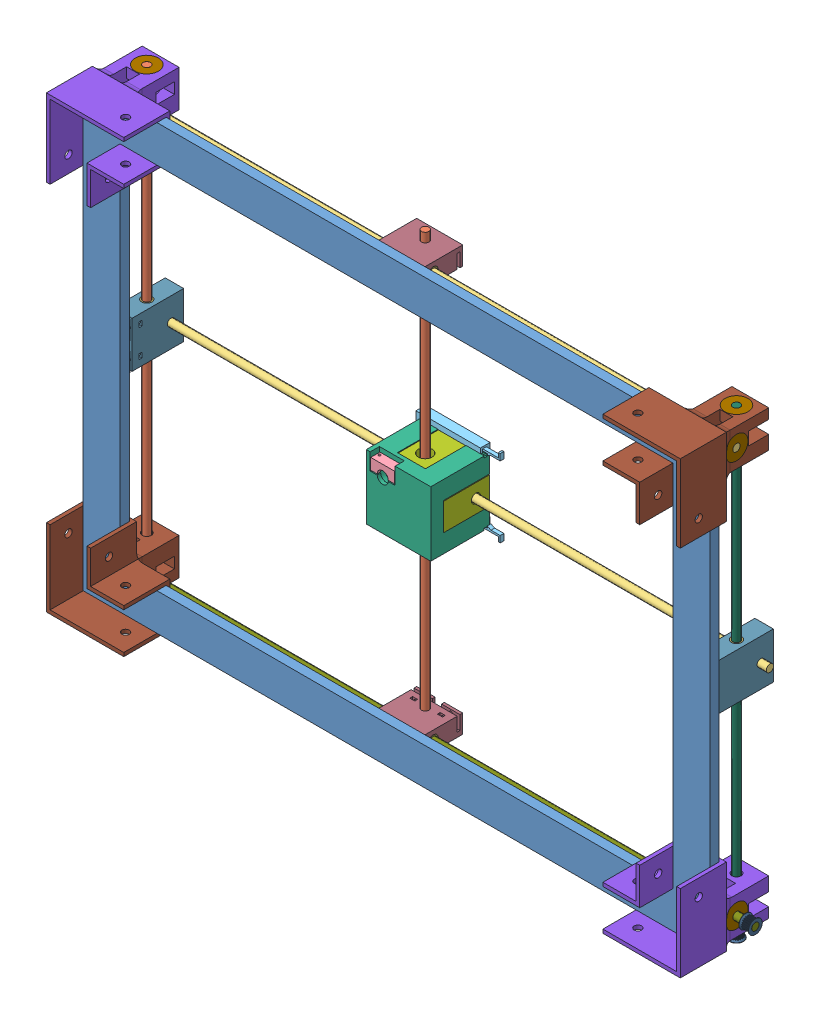
SolidWorks assembly Assemblage_XY, configuration Défaut. Lengths in mm.
Overall size (711.84 510.5 125.29).
50 component instances, 16 part files, 70 mates.
Components (placement in the parent):
- Cadre_XY-1: Cadre_XY [Défaut] at (379.0068 -247.2078 675) size (680 480 10)
- AXE_8X480-2: AXE_8X480 [Défaut] at (-280.9932 -247.2078 636) x (0.987721 0 0.156231) z (0 1 0) size (8 8 480)
- AXE_8X680-1: AXE_8X680 [Défaut] at (379.0068 212.7922 656) x (0 0.013067 0.999915) z (-1 0 0) size (8 8 680)
- AXE_8X480-3: AXE_8X480 [Défaut] at (24.9016 232.7922 639.7) x (0.999527 0 0.030742) z (0 -1 0) size (8 8 480)
- AXE_8X680-3: AXE_8X680 [Défaut] at (-300.9932 -12.6024 619.7) x (0 -0.696158 -0.717888) z (1 0 0) size (8 8 680)
- P3DMIPC-Tête_complete-1: P3DMIPC-Tête_complete [Défaut] at (-19.2911 0.7676 635.2981) x (0 1 0) z (1 0 0) size (84 69 89)
  - P3DMIPC-Clip_Buse_E3D-1: P3DMIPC-Clip_Buse_E3D [Défaut] at (17.0518 23.4109 40.0035) x (1 0 0) z (0 1 0) size (12 26 10)
  - P3DMIPC-Clip_tête-1: P3DMIPC-Clip_tête [Défaut] at (26.9018 -25.0891 4.5597) x (1 0 0) z (0 -1 0) size (84 89 10.5)
  - P3DMIPC-Porte_Buse_E3DX1-1: P3DMIPC-Porte_Buse_E3DX1 [Défaut] at (22.03 33.4019 79.1927) x (0 0 1) z (0 -1 0) size (70 70 64)
  - P3DMIPC-Chariot-1: P3DMIPC-Chariot [Défaut] at (-48.37 -30.5981 79.1927) size (70 50 70)
- Angle_magique_G-1: Angle_magique_G [Défaut] at (379.0068 -247.2078 675) x (-1 0 0) z (0 0 -1) size (91.34 90 104)
- F608ZZ-1: F608ZZ [Défaut] at (372.0068 -227.2078 656) x (0 -0.924225 -0.381849) z (1 0 0) size (25 25 7)
- Angle_magique_G-4: Angle_magique_G [Défaut] at (-300.9932 232.7922 675) x (1 0 0) z (0 0 -1) size (91.34 90 104)
- pulley_gt2_3mm_20t-10: pulley_gt2_3mm_20t [Défaut] at (-280.9932 209.5422 636) x (0.106795 0 0.994281) z (0 1 0) size (15 15 10.5)
- pulley_gt2_3mm_20t-11: pulley_gt2_3mm_20t [Défaut] at (-277.7432 212.7922 656) x (0 0.106795 0.994281) z (-1 0 0) size (15 15 10.5)
- pulley_gt2_3mm_20t-12: pulley_gt2_3mm_20t [Défaut] at (-280.9932 -236.4578 636) x (-0.771074 0 0.636745) z (0 1 0) size (15 15 10.5)
- pulley_gt2_3mm_20t-13: pulley_gt2_3mm_20t [Défaut] at (-277.7432 -227.2078 656) x (0 0.106795 0.994281) z (-1 0 0) size (15 15 10.5)
- pulley_gt2_3mm_20t-15: pulley_gt2_3mm_20t [Défaut] at (359.0068 222.0422 636) x (-0.106795 0 0.994281) z (0 -1 0) size (15 15 10.5)
- pulley_gt2_3mm_20t-16: pulley_gt2_3mm_20t [Défaut] at (368.2568 212.7922 656) x (0 0.106795 0.994281) z (-1 0 0) size (15 15 10.5)
- F608ZZ-2: F608ZZ [Défaut] at (-280.9932 225.7922 636) x (-0.546944 0 0.837169) z (0 1 0) size (25 25 7)
- F608ZZ-3: F608ZZ [Défaut] at (-293.9932 212.7922 656) x (0 0 1) z (-1 0 0) size (25 25 7)
- F608ZZ-4: F608ZZ [Défaut] at (-293.9932 -227.2078 656) x (0 0 1) z (-1 0 0) size (25 25 7)
- F608ZZ-5: F608ZZ [Défaut] at (-280.9932 -240.2078 636) x (-0.924225 0 -0.381849) z (0 -1 0) size (25 25 7)
- F608ZZ-6: F608ZZ [Défaut] at (359.0068 -240.2078 636) x (-0.546944 0 0.837169) z (0 -1 0) size (25 25 7)
- F608ZZ-7: F608ZZ [Défaut] at (372.0068 212.7922 656) x (0 0 1) z (1 0 0) size (25 25 7)
- F608ZZ-8: F608ZZ [Défaut] at (359.0068 225.7922 636) x (0 0 1) z (0 1 0) size (25 25 7)
- Angle_magique_D-1: Angle_magique_D [Défaut] at (-300.9932 -247.2078 675) x (0 1 0) z (0 0 -1) size (90 91.34 104)
- Angle_magique_D-2: Angle_magique_D [Défaut] at (379.0068 232.7922 675) x (0 -1 0) z (0 0 -1) size (90 91.34 104)
- Assemblage_glissière_block_belt_palier_AR-1: Assemblage_glissière_block_belt_palier_AR [Défaut] at (145.4265 -186.4667 609.4689) x (0 -1 0) z (-1 0 0) size (20 42 50)
  - ultimaker_cuivre_fritté_douille_8mmx11mmx22 mm-1: ultimaker_cuivre_fritté_douille_8mmx11mmx22 mm [Défaut] at (40.7411 46.5311 95.5249) size (11 11 22)
  - ultimaker_cuivre_fritté_douille_8mmx11mmx22 mm-2: ultimaker_cuivre_fritté_douille_8mmx11mmx22 mm [Défaut] at (40.7411 46.5311 123.5249) size (11 11 22)
  - Glisière_block_belt_AR-2: Glisière_block_belt_AR [Défaut] at (50.7411 14.5311 95.5249) size (20 42 50)
- Assemblage_glissière_block_belt_palier_AR-2: Assemblage_glissière_block_belt_palier_AR [Défaut] at (-95.6233 172.0511 609.4689) x (0 1 0) z (1 0 0) size (20 42 50)
  - ultimaker_cuivre_fritté_douille_8mmx11mmx22 mm-1: ultimaker_cuivre_fritté_douille_8mmx11mmx22 mm [Défaut] at (40.7411 46.5311 95.5249) size (11 11 22)
  - ultimaker_cuivre_fritté_douille_8mmx11mmx22 mm-2: ultimaker_cuivre_fritté_douille_8mmx11mmx22 mm [Défaut] at (40.7411 46.5311 123.5249) size (11 11 22)
  - Glisière_block_belt_AR-2: Glisière_block_belt_AR [Défaut] at (50.7411 14.5311 95.5249) size (20 42 50)
- pulley_gt2_3mm_20t-17: pulley_gt2_3mm_20t [Défaut] at (368.2568 -227.2078 656) x (0 0.106795 0.994281) z (-1 0 0) size (15 15 10.5)
- pulley_gt2_3mm_20t-18: pulley_gt2_3mm_20t [Défaut] at (359.0068 -223.9578 636) x (0.203502 0 0.979074) z (0 -1 0) size (15 15 10.5)
- Assemblage_glissière_block_belt_palier_GD-1: Assemblage_glissière_block_belt_palier_GD [Défaut] at (364.4936 -87.6024 626.6132) x (-1 0 0) z (0 1 0) size (20 60 50)
  - Glisière_block_belt_GD-1: Glisière_block_belt_GD [Défaut] at (15.4869 -20.6132 50) size (20 60 50)
  - ultimaker_cuivre_fritté_douille_8mmx11mmx22 mm-1: ultimaker_cuivre_fritté_douille_8mmx11mmx22 mm [Défaut] at (5.4869 9.3868 50) size (11 11 22)
  - ultimaker_cuivre_fritté_douille_8mmx11mmx22 mm-2: ultimaker_cuivre_fritté_douille_8mmx11mmx22 mm [Défaut] at (5.4869 9.3868 78) size (11 11 22)
- Assemblage_glissière_block_belt_palier_GD-2: Assemblage_glissière_block_belt_palier_GD [Défaut] at (-286.4801 62.3976 626.6132) x (1 0 0) z (0 -1 0) size (20 60 50)
  - Glisière_block_belt_GD-1: Glisière_block_belt_GD [Défaut] at (15.4869 -20.6132 50) size (20 60 50)
  - ultimaker_cuivre_fritté_douille_8mmx11mmx22 mm-1: ultimaker_cuivre_fritté_douille_8mmx11mmx22 mm [Défaut] at (5.4869 9.3868 50) size (11 11 22)
  - ultimaker_cuivre_fritté_douille_8mmx11mmx22 mm-2: ultimaker_cuivre_fritté_douille_8mmx11mmx22 mm [Défaut] at (5.4869 9.3868 78) size (11 11 22)
- AXE_8X500_Moteur-1: AXE_8X500_Moteur [Défaut] at (359.0068 -267.7078 636) x (0.283264 0 -0.959042) z (0 1 0) size (8 8 500.5)
- AXE_8X700_Moteur-1: AXE_8X700_Moteur [Défaut] at (399.5068 -227.2078 656) x (0 0 1) z (-1 0 0) size (8 8 700.5)
- pulley_gt2_3mm_20t-19: pulley_gt2_3mm_20t [Défaut] at (359.0068 -256.2078 636) x (0.203502 0 0.979074) z (0 -1 0) size (15 15 10.5)
- pulley_gt2_3mm_20t-20: pulley_gt2_3mm_20t [Défaut] at (388.0068 -227.2078 656) x (0 0.203502 0.979074) z (1 0 0) size (15 15 10.5)
Mates (geometry in assembly coordinates):
- Coaxiale1: concentric anti-aligned: cylinder of AXE_8X680-3 through (379.0068 -12.6024 619.7) axis (-1 0 0) radius 4; cylinder of P3DMIPC-Tête_complete-1/P3DMIPC-Chariot-1 through (55.9016 -12.6024 619.7) axis (1 0 0) radius 5
- Coaxiale2: concentric anti-aligned: cylinder of AXE_8X480-3 through (24.9016 -247.2078 639.7) axis (0 1 0) radius 4; cylinder of P3DMIPC-Tête_complete-1/P3DMIPC-Chariot-1 through (24.9016 -43.6024 639.7) axis (0 -1 0) radius 5
- Coïncidente14: coincident anti-aligned: plane of Cadre_XY-1 through (379.0068 -247.2078 675) normal (0 0 -1); plane of Angle_magique_G-1 through (379.0068 -247.2078 675) normal (0 0 1)
- Coïncidente15: coincident anti-aligned: plane of Cadre_XY-1 through (379.0068 -247.2078 685) normal (1 0 0); plane of Angle_magique_G-1 through (379.0068 -247.2078 725) normal (-1 0 0)
- Coïncidente16: coincident anti-aligned: plane of Cadre_XY-1 through (379.0068 -247.2078 685) normal (0 -1 0); plane of Angle_magique_G-1 through (299.0068 -247.2078 725) normal (0 1 0)
- Coïncidente27: coincident anti-aligned: plane of Cadre_XY-1 through (379.0068 -247.2078 675) normal (0 0 -1); plane of Angle_magique_G-4 through (-300.9932 232.7922 675) normal (0 0 1)
- Coïncidente28: coincident anti-aligned: plane of Cadre_XY-1 through (379.0068 232.7922 685) normal (0 1 0); plane of Angle_magique_G-4 through (-220.9932 232.7922 725) normal (0 -1 0)
- Coïncidente29: coincident anti-aligned: plane of Cadre_XY-1 through (-300.9932 -247.2078 685) normal (-1 0 0); plane of Angle_magique_G-4 through (-300.9932 232.7922 725) normal (1 0 0)
- Coaxiale17: concentric anti-aligned: cylinder of AXE_8X680-1 through (-300.9932 212.7922 656) axis (1 0 0) radius 4; cylinder of pulley_gt2_3mm_20t-11 through (-277.7432 212.7922 656) axis (-1 0 0) radius 4
- Coaxiale18: concentric aligned: cylinder of AXE_8X680-1 through (-300.9932 212.7922 656) axis (1 0 0) radius 4; cylinder of Angle_magique_G-4 through (-310.9932 212.7922 656) axis (1 0 0) radius 5
- Coïncidente30: coincident aligned: plane of Cadre_XY-1 through (-300.9932 -247.2078 685) normal (-1 0 0); plane of AXE_8X680-1 through (-300.9932 212.7922 656) normal (-1 0 0)
- Distance2: distance = 2.75 mm anti-aligned: plane of pulley_gt2_3mm_20t-11 through (-278.7432 212.7922 656) normal (1 0 0); plane of Angle_magique_G-4 through (-275.9932 192.7922 621) normal (-1 0 0)
- Coaxiale19: concentric anti-aligned: cylinder of AXE_8X680-1 through (-300.9932 212.7922 656) axis (1 0 0) radius 4; cylinder of pulley_gt2_3mm_20t-16 through (368.2568 212.7922 656) axis (-1 0 0) radius 4
- Coaxiale24: concentric aligned: cylinder of AXE_8X480-2 through (-280.9932 232.7922 636) axis (0 -1 0) radius 4; cylinder of Angle_magique_G-4 through (-280.9932 232.7923 636) axis (0 -1 0) radius 5
- Coaxiale25: concentric anti-aligned: cylinder of AXE_8X480-2 through (-280.9932 232.7922 636) axis (0 -1 0) radius 4; cylinder of pulley_gt2_3mm_20t-10 through (-280.9932 209.5422 636) axis (0 1 0) radius 4
- Coïncidente34: coincident aligned: plane of Cadre_XY-1 through (379.0068 232.7922 685) normal (0 1 0); plane of AXE_8X480-2 through (-280.9932 232.7922 636) normal (0 1 0)
- Distance4: distance = 2.75 mm anti-aligned: plane of pulley_gt2_3mm_20t-10 through (-280.9932 210.5422 636) normal (0 -1 0); plane of Angle_magique_G-4 through (-275.9932 207.7922 621) normal (0 1 0)
- Coaxiale26: concentric anti-aligned: cylinder of AXE_8X480-2 through (-280.9932 232.7922 636) axis (0 -1 0) radius 4; cylinder of pulley_gt2_3mm_20t-12 through (-280.9932 -236.4578 636) axis (0 1 0) radius 4
- Coïncidente44: coincident anti-aligned: plane of Cadre_XY-1 through (379.0068 -247.2078 675) normal (0 0 -1); plane of Angle_magique_D-1 through (-300.9932 -247.2078 675) normal (0 0 1)
- Coïncidente45: coincident anti-aligned: plane of Cadre_XY-1 through (379.0068 -247.2078 685) normal (0 -1 0); plane of Angle_magique_D-1 through (-300.9932 -247.2078 725) normal (0 1 0)
- Coïncidente46: coincident anti-aligned: plane of Cadre_XY-1 through (-300.9932 -247.2078 685) normal (-1 0 0); plane of Angle_magique_D-1 through (-300.9932 -167.2078 725) normal (1 0 0)
- Distance10: distance = 2.75 mm anti-aligned: plane of Angle_magique_D-1 through (-260.9932 -222.2078 621) normal (0 -1 0); plane of pulley_gt2_3mm_20t-12 through (-280.9932 -224.9578 636) normal (0 1 0)
- Coïncidente51: coincident anti-aligned: plane of Cadre_XY-1 through (379.0068 -247.2078 675) normal (0 0 -1); plane of Angle_magique_D-2 through (379.0068 232.7922 675) normal (0 0 1)
- Coïncidente52: coincident anti-aligned: plane of Cadre_XY-1 through (379.0068 232.7922 685) normal (0 1 0); plane of Angle_magique_D-2 through (379.0068 232.7922 725) normal (0 -1 0)
- Coïncidente53: coincident anti-aligned: plane of Cadre_XY-1 through (379.0068 -247.2078 685) normal (1 0 0); plane of Angle_magique_D-2 through (379.0068 152.7922 725) normal (-1 0 0)
- Distance11: distance = 2.75 mm anti-aligned: plane of pulley_gt2_3mm_20t-15 through (359.0068 210.5422 636) normal (0 -1 0); plane of Angle_magique_D-2 through (339.0068 207.7922 621) normal (0 1 0)
- Distance12: distance = 2.75 mm anti-aligned: plane of Angle_magique_D-2 through (354.0068 207.7922 621) normal (1 0 0); plane of pulley_gt2_3mm_20t-16 through (356.7568 212.7922 656) normal (-1 0 0)
- Coaxiale39: concentric anti-aligned: cylinder of AXE_8X680-1 through (-300.9932 212.7922 656) axis (1 0 0) radius 4; cylinder of Assemblage_glissière_block_belt_palier_AR-2/ultimaker_cuivre_fritté_douille_8mmx11mmx22 mm-1 through (21.9016 212.7922 656) axis (-1 0 0) radius 4
- Coaxiale42: concentric anti-aligned: cylinder of AXE_8X480-3 through (24.9016 -247.2078 639.7) axis (0 1 0) radius 4; cylinder of Assemblage_glissière_block_belt_palier_AR-2/Glisière_block_belt_AR-2 through (24.9016 222.7922 639.7) axis (0 -1 0) radius 4
- Coaxiale43: concentric aligned: cylinder of AXE_8X480-3 through (24.9016 -247.2078 639.7) axis (0 1 0) radius 4; cylinder of Assemblage_glissière_block_belt_palier_AR-1/Glisière_block_belt_AR-2 through (24.9016 -237.2078 639.7) axis (0 1 0) radius 4
- Coaxiale50: concentric anti-aligned: cylinder of F608ZZ-7 through (377.5068 212.7922 656) axis (-1 0 0) radius 11; cylinder of Angle_magique_D-2 through (372.0068 212.7922 656) axis (1 0 0) radius 11
- Coïncidente63: coincident anti-aligned: plane of F608ZZ-7 through (372.0068 212.7922 656) normal (-1 0 0); plane of Angle_magique_D-2 through (372.0068 212.7922 656) normal (1 0 0)
- Coaxiale51: concentric anti-aligned: cylinder of F608ZZ-8 through (359.0068 231.2922 636) axis (0 -1 0) radius 11; cylinder of Angle_magique_D-2 through (359.0068 225.7922 636) axis (0 1 0) radius 11
- Coïncidente64: coincident anti-aligned: plane of F608ZZ-8 through (359.0068 225.7922 636) normal (0 -1 0); plane of Angle_magique_D-2 through (359.0068 225.7922 636) normal (0 1 0)
- Coïncidente65: coincident anti-aligned: plane of Angle_magique_G-4 through (-280.9932 225.7922 636) normal (0 1 0); plane of F608ZZ-2 through (-280.9932 225.7922 636) normal (0 -1 0)
- Coaxiale53: concentric anti-aligned: cylinder of Angle_magique_G-4 through (-280.9932 225.7922 636) axis (0 1 0) radius 11; cylinder of F608ZZ-2 through (-280.9932 231.2922 636) axis (0 -1 0) radius 11
- Coaxiale54: concentric anti-aligned: cylinder of Angle_magique_G-4 through (-293.9932 212.7922 656) axis (-1 0 0) radius 11; cylinder of F608ZZ-3 through (-299.4932 212.7922 656) axis (1 0 0) radius 11
- Coïncidente66: coincident anti-aligned: plane of Angle_magique_G-4 through (-293.9932 212.7922 656) normal (-1 0 0); plane of F608ZZ-3 through (-293.9932 212.7922 656) normal (1 0 0)
- Coaxiale57: concentric anti-aligned: cylinder of F608ZZ-4 through (-299.4932 -227.2078 656) axis (1 0 0) radius 11; cylinder of Angle_magique_D-1 through (-293.9932 -227.2078 656) axis (-1 0 0) radius 11
- Coïncidente69: coincident anti-aligned: plane of F608ZZ-4 through (-293.9932 -227.2078 656) normal (1 0 0); plane of Angle_magique_D-1 through (-293.9932 -227.2078 656) normal (-1 0 0)
- Coïncidente70: coincident anti-aligned: plane of F608ZZ-5 through (-280.9932 -240.2078 636) normal (0 1 0); plane of Angle_magique_D-1 through (-280.9932 -240.2078 636) normal (0 -1 0)
- Coaxiale58: concentric anti-aligned: cylinder of F608ZZ-5 through (-280.9932 -245.7078 636) axis (0 1 0) radius 11; cylinder of Angle_magique_D-1 through (-280.9932 -240.2078 636) axis (0 -1 0) radius 11
- Distance14: distance = 2.75 mm anti-aligned: plane of Angle_magique_G-1 through (354.0068 -222.2078 621) normal (0 -1 0); plane of pulley_gt2_3mm_20t-18 through (359.0068 -224.9578 636) normal (0 1 0)
- Distance15: distance = 2.75 mm anti-aligned: plane of Angle_magique_G-1 through (354.0068 -207.2078 621) normal (1 0 0); plane of pulley_gt2_3mm_20t-17 through (356.7568 -227.2078 656) normal (-1 0 0)
- Coïncidente73: coincident anti-aligned: plane of Angle_magique_G-1 through (359.0068 -240.2078 636) normal (0 -1 0); plane of F608ZZ-6 through (359.0068 -240.2078 636) normal (0 1 0)
- Coaxiale61: concentric anti-aligned: cylinder of Angle_magique_G-1 through (359.0068 -240.2078 636) axis (0 -1 0) radius 11; cylinder of F608ZZ-6 through (359.0068 -245.7078 636) axis (0 1 0) radius 11
- Coïncidente74: coincident anti-aligned: plane of Angle_magique_G-1 through (372.0068 -227.2078 656) normal (1 0 0); plane of F608ZZ-1 through (372.0068 -227.2078 656) normal (-1 0 0)
- Coaxiale62: concentric anti-aligned: cylinder of Angle_magique_G-1 through (372.0068 -227.2078 656) axis (1 0 0) radius 11; cylinder of F608ZZ-1 through (377.5068 -227.2078 656) axis (-1 0 0) radius 11
- Coaxiale64: concentric anti-aligned: cylinder of AXE_8X680-3 through (379.0068 -12.6024 619.7) axis (-1 0 0) radius 4; cylinder of Assemblage_glissière_block_belt_palier_GD-1/Glisière_block_belt_GD-1 through (349.0068 -12.6024 619.7) axis (1 0 0) radius 4
- Coaxiale65: concentric anti-aligned: cylinder of Assemblage_glissière_block_belt_palier_GD-2/ultimaker_cuivre_fritté_douille_8mmx11mmx22 mm-1 through (-280.9932 -9.6024 636) axis (0 1 0) radius 4; cylinder of AXE_8X480-2 through (-280.9932 232.7922 636) axis (0 -1 0) radius 4
- Coaxiale66: concentric aligned: cylinder of AXE_8X680-3 through (379.0068 -12.6024 619.7) axis (-1 0 0) radius 4; cylinder of Assemblage_glissière_block_belt_palier_GD-2/Glisière_block_belt_GD-1 through (-270.9932 -12.6024 619.7) axis (-1 0 0) radius 4
- Coïncidente75: coincident aligned: plane of Cadre_XY-1 through (-300.9932 -247.2078 685) normal (-1 0 0); plane of AXE_8X680-3 through (-300.9932 -12.6024 619.7) normal (-1 0 0)
- Coïncidente76: coincident aligned: plane of Cadre_XY-1 through (379.0068 -247.2078 685) normal (0 -1 0); plane of AXE_8X480-3 through (24.9016 -247.2078 639.7) normal (0 -1 0)
- Distance17: distance = 2.75 mm anti-aligned: plane of pulley_gt2_3mm_20t-13 through (-278.7432 -227.2078 656) normal (1 0 0); plane of Angle_magique_D-1 through (-275.9932 -222.2078 621) normal (-1 0 0)
- Coaxiale67: concentric anti-aligned: cylinder of Angle_magique_G-1 through (389.0068 -227.2078 656) axis (-1 0 0) radius 5; cylinder of AXE_8X700_Moteur-1 through (-300.9932 -227.2078 656) axis (1 0 0) radius 4
- Coaxiale68: concentric aligned: cylinder of Assemblage_glissière_block_belt_palier_AR-1/ultimaker_cuivre_fritté_douille_8mmx11mmx22 mm-2 through (-0.0984 -227.2078 656) axis (1 0 0) radius 4; cylinder of AXE_8X700_Moteur-1 through (-300.9932 -227.2078 656) axis (1 0 0) radius 4
- Coaxiale69: concentric aligned: cylinder of Angle_magique_D-1 through (-310.9932 -227.2078 656) axis (1 0 0) radius 5; cylinder of AXE_8X700_Moteur-1 through (-300.9932 -227.2078 656) axis (1 0 0) radius 4
- Coïncidente80: coincident aligned: plane of Cadre_XY-1 through (-300.9932 -247.2078 685) normal (-1 0 0); plane of AXE_8X700_Moteur-1 through (-300.9932 -227.2078 656) normal (-1 0 0)
- Coaxiale70: concentric anti-aligned: cylinder of pulley_gt2_3mm_20t-13 through (-277.7432 -227.2078 656) axis (-1 0 0) radius 4; cylinder of AXE_8X700_Moteur-1 through (-300.9932 -227.2078 656) axis (1 0 0) radius 4
- Coaxiale71: concentric anti-aligned: cylinder of pulley_gt2_3mm_20t-17 through (368.2568 -227.2078 656) axis (-1 0 0) radius 4; cylinder of AXE_8X700_Moteur-1 through (-300.9932 -227.2078 656) axis (1 0 0) radius 4
- Coaxiale72: concentric aligned: cylinder of Assemblage_glissière_block_belt_palier_GD-1/ultimaker_cuivre_fritté_douille_8mmx11mmx22 mm-2 through (359.0068 12.3976 636) axis (0 -1 0) radius 4; cylinder of AXE_8X500_Moteur-1 through (359.0068 232.7922 636) axis (0 -1 0) radius 4
- Coaxiale73: concentric anti-aligned: cylinder of Angle_magique_G-1 through (359.0068 -247.2078 636) axis (0 1 0) radius 5; cylinder of AXE_8X500_Moteur-1 through (359.0068 232.7922 636) axis (0 -1 0) radius 4
- Coaxiale74: concentric aligned: cylinder of Angle_magique_D-2 through (359.0068 242.7922 636) axis (0 -1 0) radius 5; cylinder of AXE_8X500_Moteur-1 through (359.0068 232.7922 636) axis (0 -1 0) radius 4
- Coaxiale75: concentric aligned: cylinder of pulley_gt2_3mm_20t-15 through (359.0068 222.0422 636) axis (0 -1 0) radius 4; cylinder of AXE_8X500_Moteur-1 through (359.0068 232.7922 636) axis (0 -1 0) radius 4
- Coaxiale76: concentric aligned: cylinder of pulley_gt2_3mm_20t-18 through (359.0068 -223.9578 636) axis (0 -1 0) radius 4; cylinder of AXE_8X500_Moteur-1 through (359.0068 232.7922 636) axis (0 -1 0) radius 4
- Coïncidente81: coincident aligned: plane of Cadre_XY-1 through (379.0068 232.7922 685) normal (0 1 0); plane of AXE_8X500_Moteur-1 through (359.0068 232.7922 636) normal (0 1 0)
- Coaxiale77: concentric aligned: cylinder of AXE_8X500_Moteur-1 through (359.0068 232.7922 636) axis (0 -1 0) radius 4; cylinder of pulley_gt2_3mm_20t-19 through (359.0068 -256.2078 636) axis (0 -1 0) radius 4
- Coïncidente82: coincident aligned: plane of AXE_8X500_Moteur-1 through (359.0068 -267.7078 636) normal (0 -1 0); plane of pulley_gt2_3mm_20t-19 through (359.0068 -267.7078 636) normal (0 -1 0)
- Coïncidente83: coincident aligned: plane of AXE_8X700_Moteur-1 through (399.5068 -227.2078 656) normal (1 0 0); plane of pulley_gt2_3mm_20t-20 through (399.5068 -227.2078 656) normal (1 0 0)
- Coaxiale78: concentric aligned: cylinder of AXE_8X700_Moteur-1 through (-300.9932 -227.2078 656) axis (1 0 0) radius 4; cylinder of pulley_gt2_3mm_20t-20 through (388.0068 -227.2078 656) axis (1 0 0) radius 4
